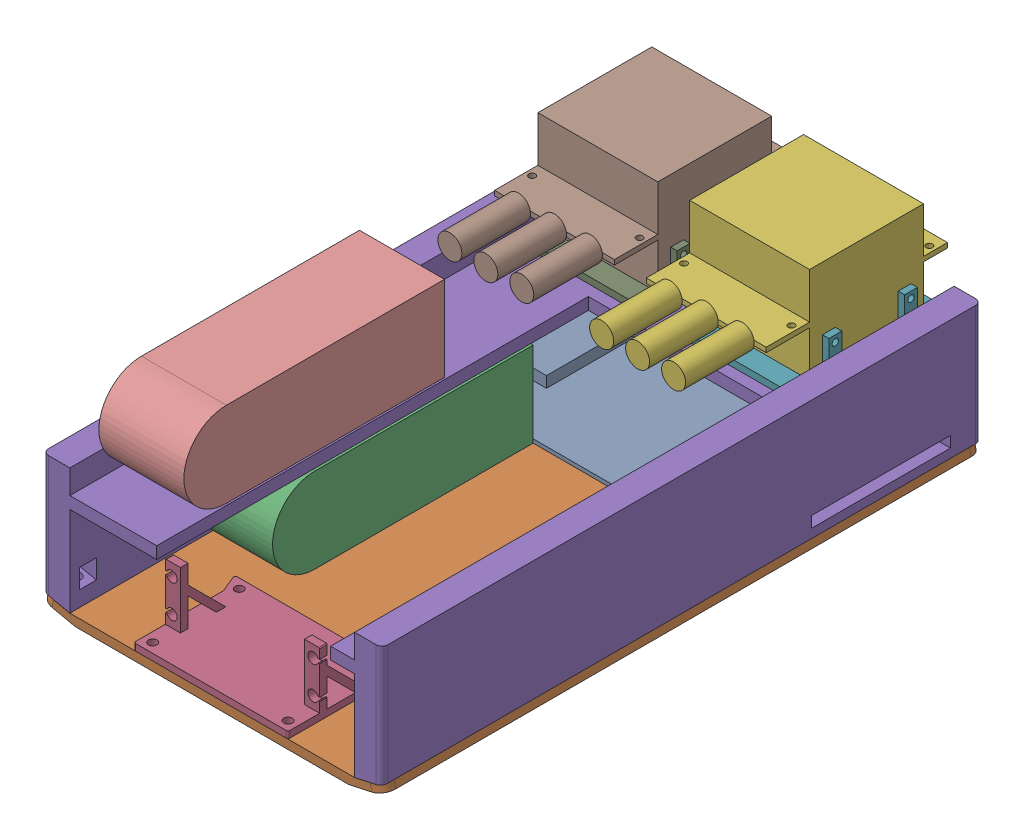
SolidWorks assembly ElecCarAssembly, configuration Default. Lengths in mm.
Overall size (181.81 113.79 317.5).
12 component instances, 7 part files, 27 mates.
Components (placement in the parent):
- PCB-1: PCB [Default] at (-90.7 4.7625 -259.08) x (-1 0 0) z (0 0 -1) size (149.86 7.84 116.84)
- VehicleBase-1: VehicleBase [Default] at (-90.065 4.7625 0) x (-1 0 0) z (0 0 -1) size (181.81 7.89 317.5)
- 6s LiPo-1: 6s LiPo [Default] at (-143.13 27.2625 -200.66) x (-1 0 0) z (0 0 1) size (45 45 138)
- ServoMount-1: ServoMount [Default] at (-131.4492 4.7625 0) size (88.99 33.5 57.5)
- VehicleChassis-1: VehicleChassis [Default] at (-89.9062 4.7625 -317.5) size (179.81 66.63 317.5)
- MotorControllerFit-1: MotorControllerFit [Default] at (-55.42 77.2767 -285.5638) x (-1 0 0) z (0 0 -1) size (70.43 55.09 132.36)
  - MotorController-1: MotorController [Default] at (-5.643 11.1095 31.9362) size (63.5 50.8 132.36)
  - MotorControllerMount-3: MotorControllerMount [Default] at (-5.7065 -18.5842 -10.9263) size (70.43 21.87 80.32)
- MotorControllerFit-2: MotorControllerFit [Default] at (-135.8055 77.2767 -285.5638) x (-1 0 0) z (0 0 -1) size (70.43 55.09 132.36)
  - MotorController-1: MotorController [Default] at (-5.643 11.1095 31.9362) size (63.5 50.8 132.36)
  - MotorControllerMount-3: MotorControllerMount [Default] at (-5.7065 -18.5842 -10.9263) size (70.43 21.87 80.32)
- 6s LiPo-2: 6s LiPo [Default] at (-142.8125 81.1925 -153.3996) x (-1 0 0) z (0 0 1) size (45 45 138)
Mates (geometry in assembly coordinates):
- Coincident1: coincident anti-aligned: plane of PCB-1 through (-90.7 4.7625 -259.08) normal (0 -1 0); plane of VehicleBase-1 through (-165.63 4.7625 -317.5) normal (0 1 0)
- Coincident2: coincident aligned: line of PCB-1 through (-165.63 4.7625 -309.88) axis (0 0 1); line of VehicleBase-1 through (-165.63 4.7625 -317.5) axis (0 0 1)
- Coincident3: coincident anti-aligned: line of PCB-1 through (-23.39 4.7625 -317.5) axis (-1 0 0); line of VehicleBase-1 through (-165.63 4.7625 -317.5) axis (1 0 0)
- Coincident8: coincident anti-aligned: plane of PCB-1 through (-165.63 6.7625 -200.66) normal (0 0 1); plane of 6s LiPo-1 through (-143.13 27.2625 -200.66) normal (0 0 -1)
- Coincident9: coincident anti-aligned: plane of VehicleBase-1 through (-165.63 4.7625 -317.5) normal (0 1 0); plane of 6s LiPo-1 through (-165.63 4.7625 -62.66) normal (0 -1 0)
- Coincident11: coincident anti-aligned: line of VehicleBase-1 through (-165.63 4.7625 -317.5) axis (0 0 1); line of 6s LiPo-1 through (-165.63 4.7625 -85.16) axis (0 0 -1)
- Coincident12: coincident anti-aligned: plane of VehicleBase-1 through (-165.63 4.7625 -317.5) normal (0 1 0); plane of ServoMount-1 through (-131.4492 4.7625 0) normal (0 -1 0)
- Parallel3: parallel aligned: line of VehicleBase-1 through (-165.63 4.7625 0) axis (1 0 0); line of ServoMount-1 through (-130.4492 8.2625 0) axis (1 0 0)
- Coincident15: coincident aligned: line of VehicleBase-1 through (-165.63 4.7625 0) axis (1 0 0); line of ServoMount-1 through (-130.4492 4.7625 0) axis (1 0 0)
- Parallel9: parallel aligned: plane of VehicleBase-1 through (-165.63 4.7625 -317.5) normal (0 1 0)
- Coincident30: coincident anti-aligned: plane of VehicleBase-1 through (-17.71 0 -317.5) normal (0 -1 0)
- Coincident34: coincident anti-aligned: plane of VehicleBase-1 through (-14.5 4.7625 -317.5) normal (-0.211002 0.977486 0); plane of VehicleChassis-1 through (-14.5 4.7625 0) normal (0.211002 -0.977486 0)
- Coincident45: coincident anti-aligned: plane of VehicleChassis-1 through (-165.3125 58.6925 0) normal (0 1 0); plane of MotorControllerFit-2/MotorControllerMount-3 through (-130.099 58.6925 -274.6375) normal (0 -1 0)
- Coincident46: coincident anti-aligned: plane of VehicleChassis-1 through (-165.3125 58.6925 0) normal (0 1 0); plane of MotorControllerFit-1/MotorControllerMount-3 through (-49.7135 58.6925 -274.6375) normal (0 -1 0)
- Parallel12: parallel anti-aligned: plane of MotorControllerFit-1/MotorController-1 through (-81.527 113.7863 -221.5) normal (-1 0 0); plane of MotorControllerFit-2/MotorController-1 through (-98.4125 113.7863 -221.5) normal (1 0 0)
- Parallel13: parallel anti-aligned: plane of VehicleChassis-1 through (-165.3125 71.3925 0) normal (1 0 0); plane of MotorControllerFit-2/MotorController-1 through (-161.9125 113.7863 -221.5) normal (-1 0 0)
- Coincident51: coincident aligned: plane of VehicleChassis-1 through (-89.9062 4.7625 -317.5) normal (0 0 -1); plane of MotorControllerFit-1/MotorController-1 through (-49.777 88.3863 -317.5) normal (0 0 -1)
- Coincident53: coincident aligned: plane of VehicleChassis-1 through (-89.9062 4.7625 -317.5) normal (0 0 -1); plane of MotorControllerFit-2/MotorController-1 through (-130.1625 88.3863 -317.5) normal (0 0 -1)
- Coincident54: coincident anti-aligned: plane of VehicleChassis-1 through (-165.3125 71.3925 0) normal (1 0 0); plane of MotorControllerFit-2/MotorControllerMount-3 through (-165.3125 62.1925 -244.475) normal (-1 0 0)
- Coincident55: coincident anti-aligned: plane of VehicleChassis-1 through (-14.5 71.3925 0) normal (-1 0 0); plane of MotorControllerFit-1/MotorControllerMount-3 through (-14.5 62.1925 -244.475) normal (1 0 0)
- Coincident56: coincident anti-aligned: plane of VehicleBase-1 through (-17.71 0 -317.5) normal (0 -1 0)
- Coincident57: coincident aligned: plane of VehicleChassis-1 through (0 7.8925 0) normal (1 0 0)
- Coincident58: coincident aligned: plane of VehicleChassis-1 through (-89.9062 4.7625 0) normal (0 0 1)
- Coincident59: coincident anti-aligned: plane of VehicleChassis-1 through (-165.3125 58.6925 0) normal (0 1 0); plane of 6s LiPo-2 through (-165.3125 58.6925 -15.3996) normal (0 -1 0)
- Coincident62: coincident anti-aligned: line of VehicleBase-1 through (0 7.8925 -311.15) axis (0 0 1); line of VehicleChassis-1 through (0 7.8925 -3.175) axis (0 0 -1)
- Coincident63: coincident anti-aligned: plane of VehicleChassis-1 through (-165.3125 71.3925 0) normal (1 0 0); plane of 6s LiPo-2 through (-165.3125 58.6925 -15.3996) normal (-1 0 0)
- Coincident65: coincident aligned: plane of VehicleBase-1 through (-90.065 4.7625 -317.5) normal (0 0 -1); plane of VehicleChassis-1 through (-89.9062 4.7625 -317.5) normal (0 0 -1)
